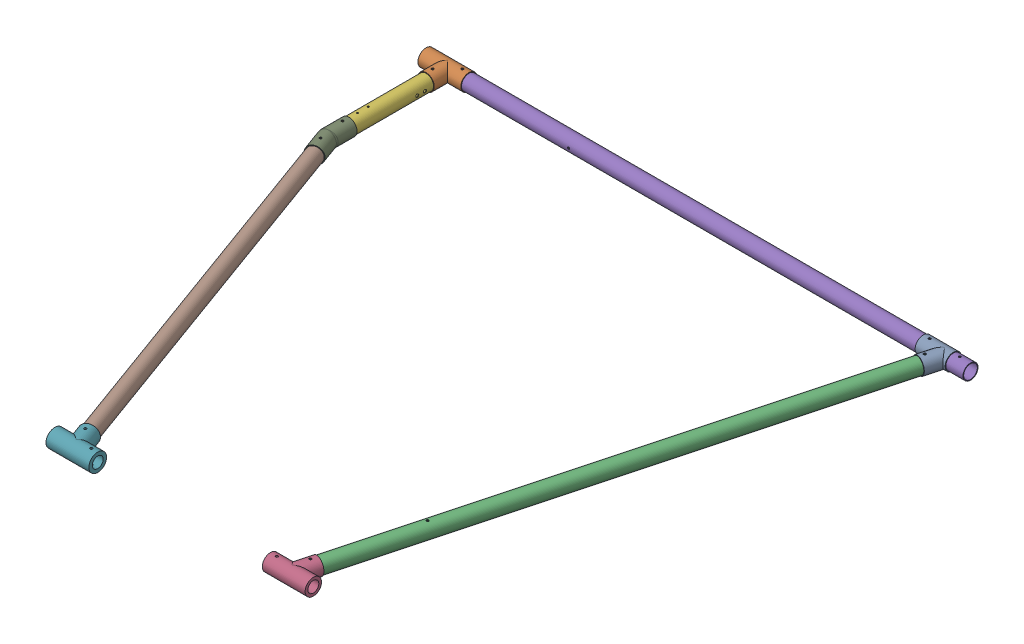
SolidWorks assembly FrameAssembly, configuration Default. Lengths in mm.
Overall size (1269.5 41.35 1240.41).
9 component instances, 9 part files, 18 mates.
Components (placement in the parent):
- Frame_005_bottomFrontConnection-1: Frame_005_bottomFrontConnection [Default] at origin size (70 38.17 72.32)
- Frame_004_bottomBackConnection-1: Frame_004_bottomBackConnection [Default] at (-1059.5 0 0) x (-1 0 0) z (0 0 1) size (100 38.17 69.09)
- Frame_003_frontTube-1: Frame_003_frontTube [Default] at (-111.2443 0 601.7718) x (-0.965926 0 -0.258819) z (-0.258819 0 0.965926) size (35 35 1200)
- Frame_001_frontKeelConnection-1: Frame_001_frontKeelConnection [Default] at (-221.7121 0 1200.6458) x (-1 0 0) z (0 0 -1) size (100 38.17 72.32)
- Frame_006_bottomTube-1: Frame_006_bottomTube [Default] at (-430 0 0) x (0 0 1) z (-1 0 0) size (35 35 1269.5)
- Frame_007_BackShortTube-1: Frame_007_BackShortTube [Default] at (-1109.5 0 140) size (35 35 240)
- Frame_002_backKeelConnection-1: Frame_002_backKeelConnection [Default] at (-824.4123 0 1200.6458) x (1 0 0) z (0 0 -1) size (100 41.35 74.73)
- Frame_008_backLongTube-1: Frame_008_backLongTube [Default] at (-943.3703 0 736.4376) x (0 -1 0) z (0.34202 0 0.939693) size (35 35 948)
- Frame_009_backElbow-1: Frame_009_backElbow [Default] at (-1109.5 0 230) x (1 0 0) z (0 -1 0) size (54.12 103.51 38.17)
Mates (geometry in assembly coordinates):
- Coincident1: coordinate: point of Frame_005_bottomFrontConnection-1
- Concentric2: concentric anti-aligned: cylinder of Frame_005_bottomFrontConnection-1 through (58.1216 0 -30.3101) axis (-0.258819 0 0.965926) radius 17.5; cylinder of Frame_003_frontTube-1 through (-266.5357 0 1181.3273) axis (0.258819 0 -0.965926) radius 17.5
- Concentric3: concentric aligned: cylinder of Frame_005_bottomFrontConnection-1 through (40.1649 0 36.7052) axis (0 1 0) radius 2.75; cylinder of Frame_003_frontTube-1 through (40.1649 0 36.7052) axis (0 1 0) radius 2.75
- Concentric4: concentric aligned: cylinder of Frame_003_frontTube-1 through (-266.5357 0 1181.3273) axis (0.258819 0 -0.965926) radius 17.5; cylinder of Frame_001_frontKeelConnection-1 through (-279.8336 0 1230.9559) axis (0.258819 0 -0.965926) radius 17.0875
- Concentric5: concentric aligned: cylinder of Frame_003_frontTube-1 through (-262.6534 0 1166.8384) axis (0 1 0) radius 2.75; cylinder of Frame_001_frontKeelConnection-1 through (-262.6534 0 1166.8384) axis (0 1 0) radius 2.75
- Concentric6: concentric anti-aligned: cylinder of Frame_005_bottomFrontConnection-1 through (100 0 0) axis (-1 0 0) radius 17.5; cylinder of Frame_006_bottomTube-1 through (-970 0 0) axis (1 0 0) radius 17.5
- Concentric11: concentric aligned: cylinder of Frame_004_bottomBackConnection-1 through (-1159.5 0 0) axis (1 0 0) radius 17.5; cylinder of Frame_006_bottomTube-1 through (-970 0 0) axis (1 0 0) radius 15.9125
- Parallel3: parallel aligned: plane of Frame_004_bottomBackConnection-1 through (-1109.5 0 50) normal (0 0 1)
- Concentric12: concentric anti-aligned: cylinder of Frame_004_bottomBackConnection-1 through (-1109.5 0 -19.0885) axis (0 0 1) radius 17.5; cylinder of Frame_007_BackShortTube-1 through (-1109.5 0 260) axis (0 0 -1) radius 17.5
- Concentric13: concentric aligned: cylinder of Frame_004_bottomBackConnection-1 through (-1109.5 0 35) axis (0 1 0) radius 2.75; cylinder of Frame_007_BackShortTube-1 through (-1109.5 0 35) axis (0 1 0) radius 2.75
- Concentric15: concentric aligned: cylinder of Frame_002_backKeelConnection-1 through (-761.9182 0 1234.9732) axis (-0.34202 0 -0.939693) radius 17.5; cylinder of Frame_008_backLongTube-1 through (-781.2527 0 1181.8519) axis (-0.34202 0 -0.939693) radius 17.5
- Concentric16: concentric aligned: cylinder of Frame_002_backKeelConnection-1 through (-786.383 0 1167.7566) axis (0 1 0) radius 2.75; cylinder of Frame_008_backLongTube-1 through (-786.383 0 1167.7566) axis (0 1 0) radius 2.75
- Concentric17: concentric anti-aligned: cylinder of Frame_007_BackShortTube-1 through (-1109.5 0 260) axis (0 0 -1) radius 17.5; cylinder of Frame_009_backElbow-1 through (-1109.5 0 230) axis (0 0 1) radius 17.5
- Concentric18: concentric anti-aligned: cylinder of Frame_008_backLongTube-1 through (-781.2527 0 1181.8519) axis (-0.34202 0 -0.939693) radius 17.5; cylinder of Frame_009_backElbow-1 through (-1111.856 0 273.5268) axis (0.34202 0 0.939693) radius 17.5
- Concentric20: concentric anti-aligned: cylinder of Frame_001_frontKeelConnection-1 through (-221.7121 0 1200.6458) axis (-1 0 0) radius 12.7; cylinder of Frame_002_backKeelConnection-1 through (-824.4123 0 1200.6458) axis (1 0 0) radius 12.7
- Concentric21: concentric aligned: cylinder of Frame_007_BackShortTube-1 through (-1109.5 0 245) axis (0 1 0) radius 2.75; cylinder of Frame_009_backElbow-1 through (-1109.5 0 245) axis (0 1 0) radius 2.75
- Concentric22: concentric anti-aligned: cylinder of Frame_004_bottomBackConnection-1 through (-1074.5 0 0) axis (0 -1 0) radius 2.75; cylinder of Frame_006_bottomTube-1 through (-1074.5 -17.5 0) axis (0 1 0) radius 2.75
- Concentric25: concentric aligned: cylinder of Frame_005_bottomFrontConnection-1 through (15 0 0) axis (0 -1 0) radius 2.75; cylinder of Frame_006_bottomTube-1 through (15 0 0) axis (0 -1 0) radius 2.75
